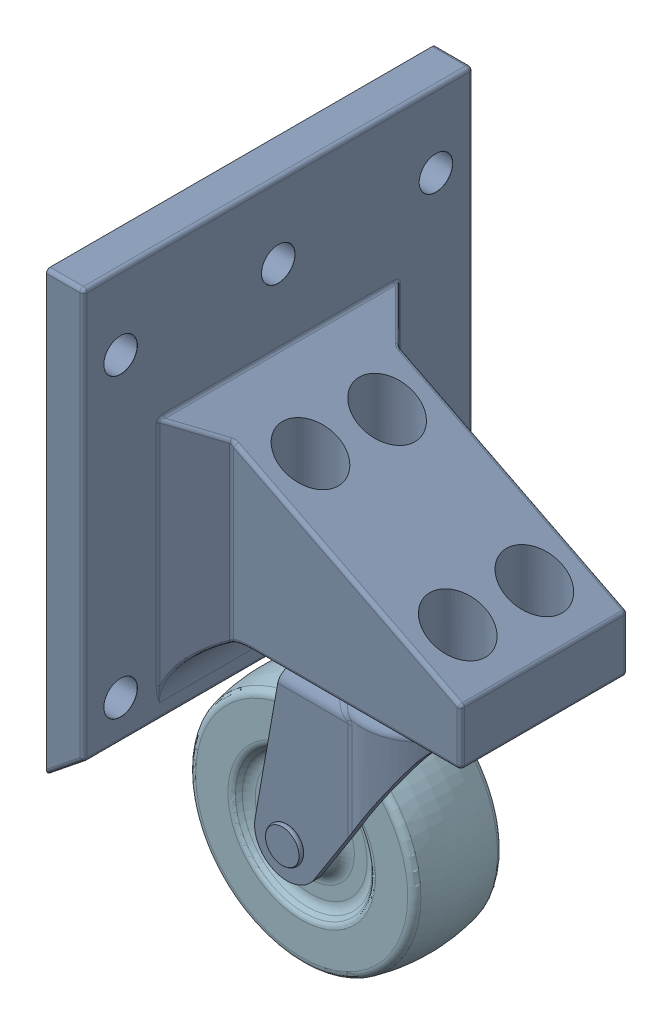
SolidWorks assembly Rear Caster Wheel_ASM, configuration Default. Lengths in mm.
Overall size (85.23 169.99 105).
2 component instances, 2 part files, 3 mates.
Components (placement in the parent):
- 22785T42_Tight-Quarters Swivel Caster-1: 22785T42_Tight-Quarters Swivel Caster [22785T42] at (91.7837 -28.4822 28.2278) size (77.79 78.58 34.1)
- Rear Caster Mount_V2-1: Rear Caster Mount_V2 [Default] at (42.9274 23.7208 28.2216) size (81.7 118.04 105)
Mates (geometry in assembly coordinates):
- Coincident2: coincident anti-aligned: plane of 22785T42_Tight-Quarters Swivel Caster-1 through (91.7837 10.8084 28.2278) normal (0 1 0); plane of Castor mount mcmastercarr v2-1 through (134.6274 10.8084 5.7216) normal (0 -1 0)
- Concentric2: concentric aligned: cylinder of 22785T42_Tight-Quarters Swivel Caster-1 through (111.6274 10.8084 38.5466) axis (0 -1 0) radius 2.3813; cylinder of Castor mount mcmastercarr v2-1 through (111.6274 70.8084 38.5466) axis (0 -1 0) radius 2.38
- Parallel2: parallel aligned: plane of 22785T42_Tight-Quarters Swivel Caster-1 through (117.1837 10.8084 13.1466) normal (1 0 0); plane of Castor mount mcmastercarr v2-1 through (124.6274 23.7208 28.2216) normal (1 0 0)
